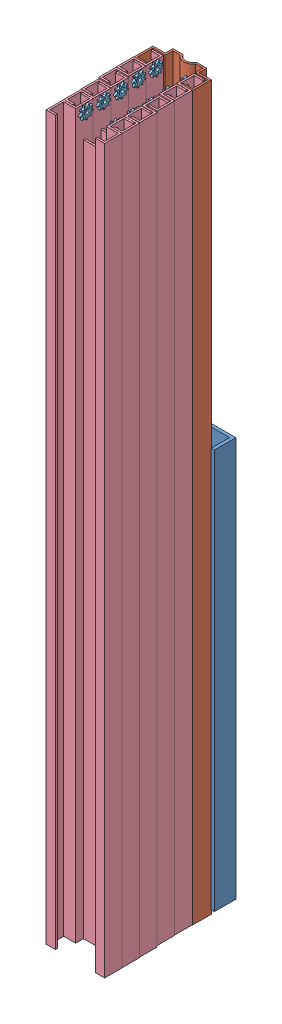
SolidWorks assembly Assem1, configuration Default. Lengths in mm.
Overall size (210 2364.61 416.58).
18 component instances, 5 part files, 27 mates.
Components (placement in the parent):
- Part2-1: Part2 [Default] at (977.9066 -10.8653 1777.8241) size (210 1300 70)
- Part1-1: Part1 [Default] at (1072.9066 1026.7551 1833.4072) size (190 2350 87)
- Part5-1: Part5 [Default] at (1072.9066 1065.8987 1741.8241) x (0.488393 0 0.872624) z (0 1 0) size (48 48 500)
- Part3-1: Part3 [Default] at (1072.9066 1027.7513 1890.4072) size (190 2350 108)
- Part3-2: Part3 [Default] at (1072.9066 1026.7608 1947.4072) size (190 2350 108)
- Part3-3: Part3 [Default] at (1072.9066 1022.4446 2004.4072) size (190 2350 108)
- Part3-4: Part3 [Default] at (1072.9066 1021.1907 2061.4072) size (190 2350 108)
- Part4-1: Part4 [Default] at (1024.0069 3356.7608 1873.9072) x (1 0 0) z (0 -0.928456 0.371443) size (9.5 43.8 44.47)
- Part4-2: Part4 [Default] at (1114.5064 3356.7608 1873.9072) size (9.5 43.8 44.47)
- Part4-3: Part4 [Default] at (1024.0069 3352.4446 1930.9072) size (9.5 43.8 44.47)
- Part4-4: Part4 [Default] at (1114.5064 3351.1907 1987.9072) size (9.5 43.8 44.47)
- Part4-5: Part4 [Default] at (1114.5064 3357.7513 1816.9072) size (9.5 43.8 44.47)
- Part4-6: Part4 [Default] at (1024.0069 3351.1907 1987.9072) size (9.5 43.8 44.47)
- Part4-7: Part4 [Default] at (1024.0069 3357.7513 1816.9072) size (9.5 43.8 44.47)
- Part4-8: Part4 [Default] at (1114.5064 3352.4446 1930.9072) x (1 0 0) z (0 -0.510675 -0.859774) size (9.5 43.8 44.47)
- Part3-5: Part3 [Default] at (1072.9066 1020.694 2118.4072) size (190 2350 108)
- Part4-9: Part4 [Default] at (1024.0069 3350.694 2044.9072) size (9.5 43.8 44.47)
- Part4-10: Part4 [Default] at (1114.5064 3350.694 2044.9072) size (9.5 43.8 44.47)
Mates (geometry in assembly coordinates):
- Parallel1: parallel aligned: plane of Part2-1 through (977.9066 2339.1347 1777.8241) normal (0 1 0); plane of Part1-1 through (1072.9066 3376.7551 1741.8241) normal (0 1 0)
- Concentric2: concentric anti-aligned: cylinder of Part1-1 through (1072.9066 1026.7551 1741.8241) axis (0 1 0) radius 24; cylinder of Part5-1 through (1072.9066 1565.8987 1741.8241) axis (0 -1 0) radius 24
- Tangent2: tangent aligned: cylinder of Part1-1 through (1072.9066 1026.7551 1741.8241) axis (0 1 0) radius 24; cylinder of Part5-1 through (1072.9066 1565.8987 1741.8241) axis (0 -1 0) radius 24
- Tangent3: tangent anti-aligned: plane of Part2-1 through (977.9066 1039.1347 1717.8241) normal (0 0 1); cylinder of Part5-1 through (1072.9066 1565.8987 1741.8241) axis (0 -1 0) radius 24
- Coincident3: coincident anti-aligned: plane of Part2-1 through (977.9066 1039.1347 1777.8241) normal (1 0 0); plane of Part1-1 through (977.9066 1026.7551 1777.4072) normal (-1 0 0)
- Coincident10: coincident anti-aligned: plane of Part1-1 through (977.9066 1026.7551 1839.4072) normal (0 0 1); plane of Part3-1 through (977.9066 1027.7512 1839.4072) normal (0 0 -1)
- Coincident11: coincident anti-aligned: plane of Part1-1 through (1131.9066 1026.7551 1839.4072) normal (0 0 1); plane of Part3-1 through (1167.9066 3377.7513 1839.4072) normal (0 0 -1)
- Parallel6: parallel aligned: plane of Part1-1 through (1167.9066 1026.7551 1839.4072) normal (1 0 0); plane of Part3-1 through (1167.9066 3377.7513 1845.4072) normal (1 0 0)
- Coincident13: coincident anti-aligned: line of Part1-1 through (1167.9066 1026.7551 1839.4072) axis (0 1 0); line of Part3-1 through (1167.9066 3377.7513 1839.4072) axis (0 -1 0)
- Coincident14: coincident anti-aligned: plane of Part3-1 through (1072.9066 1027.7513 1896.4072) normal (0 0 1); plane of Part3-2 through (1167.9066 3376.7608 1896.4072) normal (0 0 -1)
- Coincident15: coincident anti-aligned: line of Part3-1 through (1167.9066 1027.7513 1896.4072) axis (0 1 0); line of Part3-2 through (1167.9066 3376.7608 1896.4072) axis (0 -1 0)
- Coincident16: coincident anti-aligned: plane of Part3-2 through (1072.9066 1026.7608 1953.4072) normal (0 0 1); plane of Part3-3 through (1167.9066 3372.4446 1953.4072) normal (0 0 -1)
- Coincident17: coincident anti-aligned: line of Part3-2 through (1167.9066 1026.7608 1953.4072) axis (0 1 0); line of Part3-3 through (1167.9066 3372.4446 1953.4072) axis (0 -1 0)
- Coincident18: coincident anti-aligned: plane of Part3-3 through (1072.9066 1022.4446 2010.4072) normal (0 0 1); plane of Part3-4 through (1167.9066 3371.1907 2010.4072) normal (0 0 -1)
- Coincident19: coincident anti-aligned: line of Part3-3 through (1167.9066 1022.4446 2010.4072) axis (0 1 0); line of Part3-4 through (1167.9066 3371.1907 2010.4072) axis (0 -1 0)
- Coincident25: coincident anti-aligned: circle of Part3-2; circle of Part4-2
- Coincident26: coincident anti-aligned: circle of Part3-2; circle of Part4-1
- Coincident27: coincident anti-aligned: circle of Part3-3; circle of Part4-8
- Coincident28: coincident anti-aligned: circle of Part3-1; circle of Part4-5
- Coincident29: coincident anti-aligned: circle of Part3-4; circle of Part4-4
- Coincident30: coincident anti-aligned: circle of Part3-1; circle of Part4-7
- Coincident31: coincident anti-aligned: circle of Part3-3; circle of Part4-3
- Coincident32: coincident anti-aligned: circle of Part3-4; circle of Part4-6
- Coincident33: coincident anti-aligned: line of Part3-4 through (1167.9066 1021.1907 2067.4072) axis (0 1 0); line of Part3-5 through (1167.9066 3370.694 2067.4072) axis (0 -1 0)
- Coincident34: coincident anti-aligned: plane of Part3-4 through (1072.9066 1021.1907 2067.4072) normal (0 0 1); plane of Part3-5 through (1167.9066 3370.694 2067.4072) normal (0 0 -1)
- Coincident36: coincident anti-aligned: circle of Part3-5; circle of Part4-9
- Coincident37: coincident anti-aligned: circle of Part3-5; circle of Part4-10
